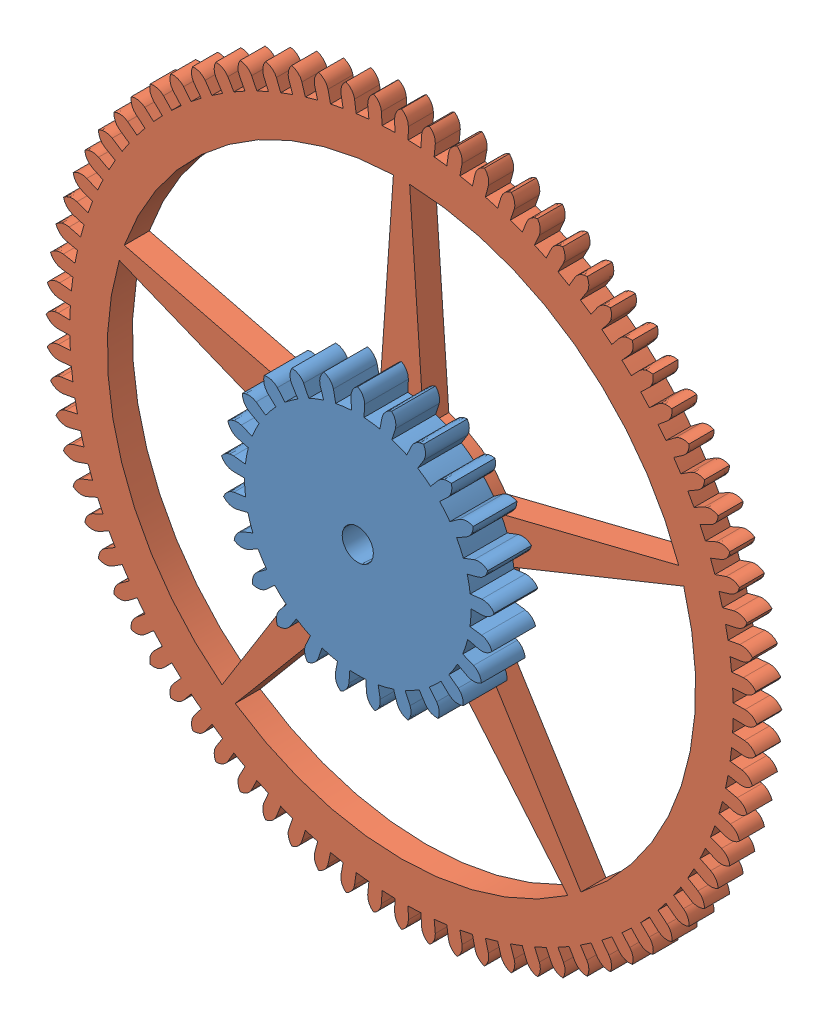
SolidWorks assembly motionwork reduction assy, configuration Default. Lengths in mm.
Overall size (56.89 56.89 5.5).
2 component instances, 2 part files, 2 mates.
Components (placement in the parent):
- motionwork reduction pinion-1: motionwork reduction pinion [Default] at origin size (21.83 21.79 5.5)
- motionwork reduction wheel-1: motionwork reduction wheel [Default] at origin size (56.89 56.89 2)
Mates (geometry in assembly coordinates):
- Coincident1: coincident: plane of motionwork reduction pinion-1 through (0 0 0) normal (0 0 -1); plane of motionwork reduction wheel-1 through (0.55 -12.5055 0) normal (0 0 1)
- Concentric1: concentric: cylinder of motionwork reduction pinion-1 through (0 -40 -2) axis (0 0 1) radius 4; cylinder of motionwork reduction wheel-1 through (0 -40 -2) axis (0 0 1) radius 4
